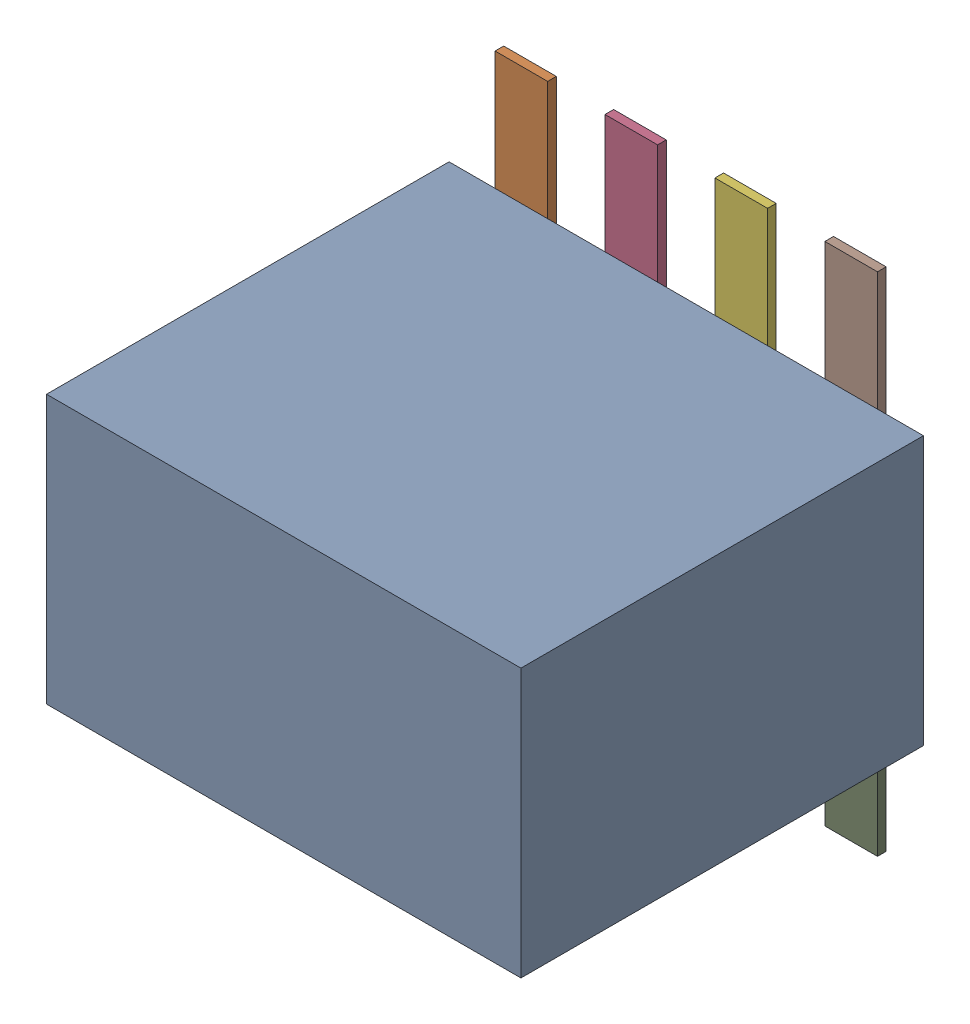
SolidWorks assembly 9452610336, configuration Default. Lengths in mm.
Overall size (5.48 5.85 4.75).
2 component instances, 2 part files, 0 mates.
Components (placement in the parent):
- Body-0-1: Body-0 [Default] at (0 0 0.1) size (5.48 3.1 4.65)
- Pins-1-1: Pins-1 [Default] at origin size (4.42 5.85 0.1)
